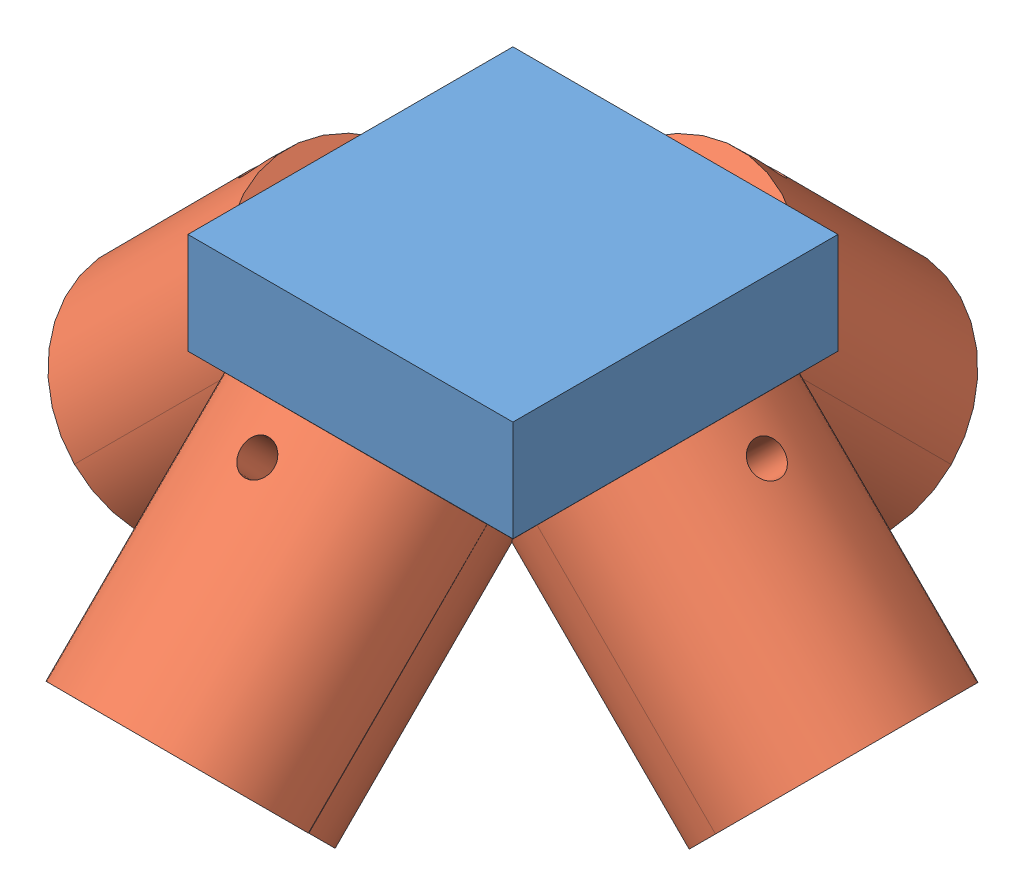
SolidWorks assembly Acople integrado, configuration Predeterminado. Lengths in mm.
Overall size (79.56 37.79 79.72).
10 component instances, 2 part files, 6 mates.
Components (placement in the parent):
- Acople final-1: Acople final [Predeterminado] at (17.4711 4.5035 63.2502) size (63.12 37.79 63.25)
  - Base final-1: Base final [Predeterminado] at (22.7654 1.2928 32) size (32 22.43 32)
  - Cilindro de base 4 puntos_6-1: Cilindro de base 4 puntos_6 [Predeterminado] at (-16.7159 -5.7926 20.8119) x (0 -0.707107 -0.707107) z (1 0 0) size (24.84 11.63 23.26)
  - Cilindro de base 4 puntos_6-2: Cilindro de base 4 puntos_6 [Predeterminado] at (-43.918 -5.7769 48) x (-0.707107 -0.707107 0) z (0 0 -1) size (24.84 11.63 23.26)
  - Cilindro de base 4 puntos_6-3: Cilindro de base 4 puntos_6 [Predeterminado] at (10.5151 -5.748 48) x (0.707107 -0.707107 0) z (0 0 1) size (24.84 11.63 23.26)
  - Cilindro de base 4 puntos_6-4: Cilindro de base 4 puntos_6 [Predeterminado] at (-16.7159 -5.6015 75.3793) x (0 -0.707107 0.707107) z (-1 0 0) size (24.84 11.63 23.26)
- Cilindro de base 4 puntos_6-1: Cilindro de base 4 puntos_6 [Predeterminado] at (-26.4469 -1.2734 111.2502) x (-0.707107 -0.707107 0) z (0 0 1) size (24.84 11.63 23.26)
- Cilindro de base 4 puntos_6-2: Cilindro de base 4 puntos_6 [Predeterminado] at (27.9863 -1.2444 111.2502) x (0.707107 -0.707107 0) z (0 0 -1) size (24.84 11.63 23.26)
- Cilindro de base 4 puntos_6-3: Cilindro de base 4 puntos_6 [Predeterminado] at (0.7552 -1.2891 84.0621) x (0 -0.707107 -0.707107) z (-1 0 0) size (24.84 11.63 23.26)
- Cilindro de base 4 puntos_6-4: Cilindro de base 4 puntos_6 [Predeterminado] at (0.7369 -1.0821 138.6453) x (-0.001245 -0.707106 0.707106) z (0.999999 -0.00088 0.00088) size (24.84 11.63 23.26)
Mates (geometry in assembly coordinates):
- Coincidente2: coincident anti-aligned: cylinder of Acople final-1/Cilindro de base 4 puntos_6-4 through (0.7552 -26.0588 92.8797) axis (0 0.707107 0.707107) radius 1.65; circle of Cilindro de base 4 puntos_6-4
- Coincidente8: coincident anti-aligned: circle of Acople final-1/Cilindro de base 4 puntos_6-2; circle of Cilindro de base 4 puntos_6-1
- Coincidente9: coincident anti-aligned: circle of Acople final-1/Cilindro de base 4 puntos_6-1; circle of Cilindro de base 4 puntos_6-3
- Coincidente10: coincident aligned: plane of Acople final-1/Cilindro de base 4 puntos_6-1 through (-10.8756 -5.6305 79.7207) normal (0 -0.707107 -0.707107); plane of Cilindro de base 4 puntos_6-3 through (12.386 -5.6305 79.7207) normal (0 -0.707107 -0.707107)
- Coincidente11: coincident anti-aligned: circle of Acople final-1/Cilindro de base 4 puntos_6-3; circle of Cilindro de base 4 puntos_6-2
- Coincidente12: coincident aligned: plane of Acople final-1/Cilindro de base 4 puntos_6-3 through (32.3277 -5.5858 99.6194) normal (0.707107 -0.707107 0); plane of Cilindro de base 4 puntos_6-2 through (32.3277 -5.5858 122.881) normal (0.707107 -0.707107 0)
